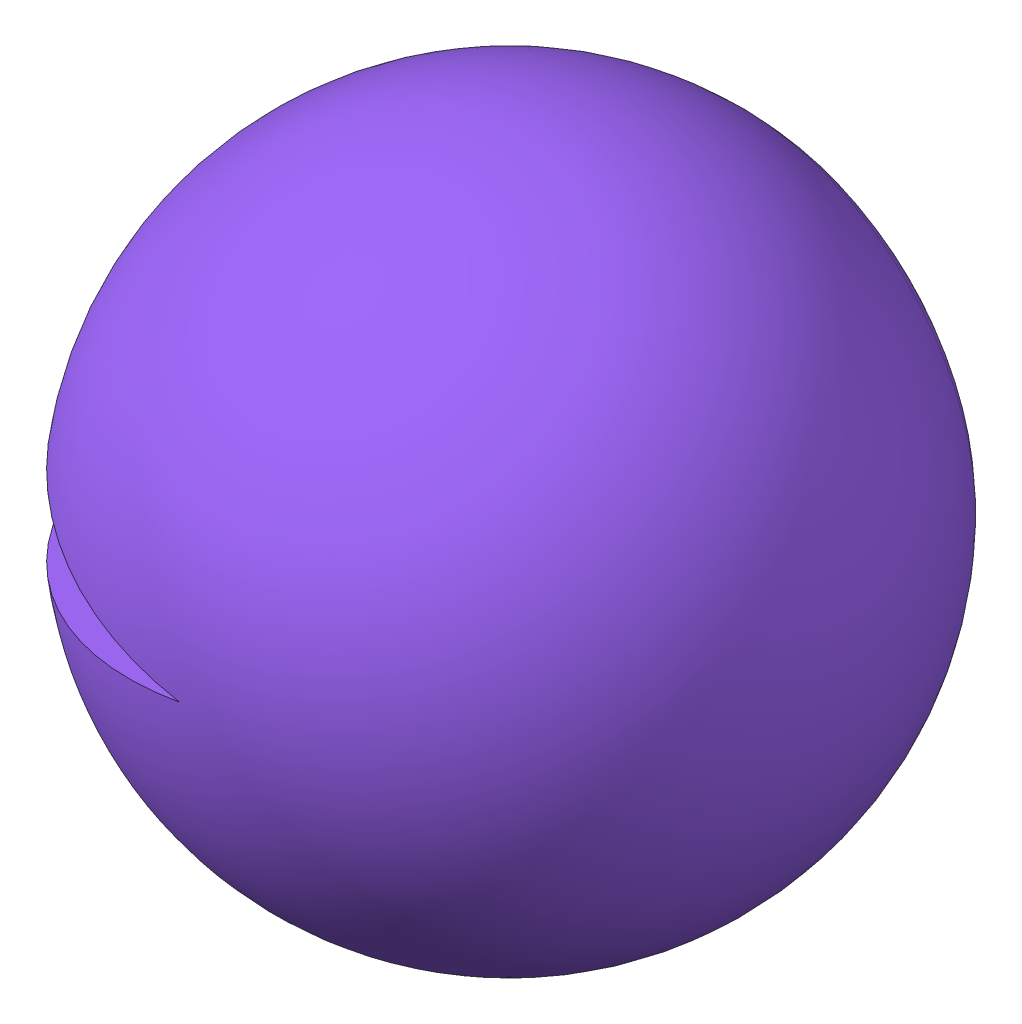
SolidWorks assembly ER3-600 机器人数模 V1.1（2016）, configuration 默认. Lengths in mm.
Overall size (1176.61 1185.62 1099.22).
8 component instances, 8 part files, 22 mates.
Components (placement in the parent):
- 底座^ER3-600 机器人数模 V1.1（2016）-1: 底座^ER3-600 机器人数模 V1.1（2016） [默认] at (-25 0 9) x (-1 0 0) z (0 1 0) size (359.06 217.5 223.77) (virtual)
- 转座^ER3-600 机器人数模 V1.1（2016）-1: 转座^ER3-600 机器人数模 V1.1（2016） [默认] at (-18 0 187.5) x (-1 0 0) z (0 1 0) size (187.42 246.08 222.85) (virtual)
- 大臂^ER3-600 机器人数模 V1.1（2016）-1: 大臂^ER3-600 机器人数模 V1.1（2016） [默认] at (-25 0 9) x (-1 0 0) z (0 1 0) size (166.87 440.16 206.04) (virtual)
- 电机座^ER3-600 机器人数模 V1.1（2016）-1: 电机座^ER3-600 机器人数模 V1.1（2016） [默认] at (0.5 57 678.5) x (1 0 0) z (0 -1 0) size (181.5 136 130.5) (virtual)
- 手腕体^ER3-600 机器人数模 V1.1（2016）-1: 手腕体^ER3-600 机器人数模 V1.1（2016） [默认] at (92.5 0 699.5) x (1 0 0) z (0 -1 0) size (246.5 104.96 129) (virtual)
- 手腕^ER3-600 机器人数模 V1.1（2016）-1: 手腕^ER3-600 机器人数模 V1.1（2016） [默认] at (295.5 0 699.5) size (112 65.5 76) (virtual)
- 法兰^ER3-600 机器人数模 V1.1（2016）-2: 法兰^ER3-600 机器人数模 V1.1（2016） [默认] at (295.5 0 699.5) size (9.5 40 40) (virtual)
- 运动范围^ER3-600 机器人数模 V1.1（2016）-1: 运动范围^ER3-600 机器人数模 V1.1（2016） [默认] x (1 0 0) z (0 -1 0) size (1176.61 1099.22 1185.62) (virtual)
Mates (geometry in assembly coordinates):
- 重合5: coordinate: point of ?
- 同心1: concentric aligned: cylinder of 底座^ER3-600 机器人数模 V1.1（2016）-1 through (0 0 121.5033) axis (0 0 -1) radius 35.25; cylinder of 转座^ER3-600 机器人数模 V1.1（2016）-1 through (0 0 369.3919) axis (0 0 -1) radius 56
- 距离1: distance = 11.5 mm anti-aligned: plane of 转座^ER3-600 机器人数模 V1.1（2016）-1 through (-18 0 192.5) normal (0 0 -1); plane of 底座^ER3-600 机器人数模 V1.1（2016）-1 through (-25 0 181) normal (0 0 1)
- LimitAngle1: limit planar angle = 0 rad aligned: plane of 底座^ER3-600 机器人数模 V1.1（2016）-1 through (-25 0 9) normal (0 1 0); plane of 转座^ER3-600 机器人数模 V1.1（2016）-1 through (-18 0 187.5) normal (0 1 0)
- 同心2: concentric aligned: cylinder of 转座^ER3-600 机器人数模 V1.1（2016）-1 through (0 -42.5 367.5) axis (0 -1 0) radius 46; cylinder of 大臂^ER3-600 机器人数模 V1.1（2016）-1 through (0 48.5 367.5) axis (0 -1 0) radius 51
- 距离2: distance = 2 mm anti-aligned: plane of 大臂^ER3-600 机器人数模 V1.1（2016）-1 through (-56.166 -42.5 311.334) normal (0 -1 0); plane of 转座^ER3-600 机器人数模 V1.1（2016）-1 through (192.5 -44.5 307.5) normal (0 1 0)
- LimitAngle2: limit planar angle = 0 rad aligned: plane of 转座^ER3-600 机器人数模 V1.1（2016）-1; plane of 大臂^ER3-600 机器人数模 V1.1（2016）-1
- 同心3: concentric aligned: cylinder of 大臂^ER3-600 机器人数模 V1.1（2016）-1 through (0 -56 662.5) axis (0 -1 0) radius 45.25; cylinder of 电机座^ER3-600 机器人数模 V1.1（2016）-1 through (0 104.1076 662.5) axis (0 -1 0) radius 46
- 距离3: distance = 2 mm anti-aligned: plane of 电机座^ER3-600 机器人数模 V1.1（2016）-1 through (0 56.5 662.5) normal (0 1 0); plane of 大臂^ER3-600 机器人数模 V1.1（2016）-1 through (50.6 58.5 611.9) normal (0 -1 0)
- LimitAngle3: limit planar angle = 0 rad aligned: plane of 大臂^ER3-600 机器人数模 V1.1（2016）-1; plane of 电机座^ER3-600 机器人数模 V1.1（2016）-1 through (0.5 57 678.5) normal (0 0 1)
- 同心4: concentric aligned: cylinder of 电机座^ER3-600 机器人数模 V1.1（2016）-1 through (-65.7939 0 699.5) axis (1 0 0) radius 42; cylinder of 手腕体^ER3-600 机器人数模 V1.1（2016）-1 through (84.5 0 699.5) axis (1 0 0) radius 41
- 距离4: distance = 1 mm anti-aligned: plane of 手腕体^ER3-600 机器人数模 V1.1（2016）-1 through (85.5 0 699.5) normal (-1 0 0); plane of 电机座^ER3-600 机器人数模 V1.1（2016）-1 through (84.5 -30 717.5) normal (1 0 0)
- LimitAngle5: limit planar angle = 0 rad aligned: plane of 手腕体^ER3-600 机器人数模 V1.1（2016）-1 through (92.5 0 699.5) normal (0 0 1); plane of 电机座^ER3-600 机器人数模 V1.1（2016）-1 through (0.5 57 678.5) normal (0 0 1)
- 同心5: concentric aligned: cylinder of 手腕体^ER3-600 机器人数模 V1.1（2016）-1 through (295.5 -32.5 699.5) axis (0 1 0) radius 24.5; cylinder of 手腕^ER3-600 机器人数模 V1.1（2016）-1 through (295.5 -32.5 699.5) axis (0 1 0) radius 24.5
- 距离5: distance = 5.5 mm anti-aligned: plane of 手腕^ER3-600 机器人数模 V1.1（2016）-1 through (295.5 27.5 699.5) normal (0 1 0); plane of 手腕体^ER3-600 机器人数模 V1.1（2016）-1 through (92.5 33 699.5) normal (0 -1 0)
- LimitAngle6: limit planar angle = 0 rad aligned: plane of 手腕^ER3-600 机器人数模 V1.1（2016）-1 through (295.5 0 699.5) normal (1 0 0); plane of 手腕体^ER3-600 机器人数模 V1.1（2016）-1
- 同心6: concentric aligned: cylinder of 手腕^ER3-600 机器人数模 V1.1（2016）-1 through (374 0 699.5) axis (-1 0 0) radius 20; cylinder of 法兰^ER3-600 机器人数模 V1.1（2016）-2 through (374 0 699.5) axis (-1 0 0) radius 20
- 距离6: distance = 4.5 mm aligned: plane of 法兰^ER3-600 机器人数模 V1.1（2016）-2 through (374 0 699.5) normal (1 0 0); plane of 手腕^ER3-600 机器人数模 V1.1（2016）-1 through (369.5 0 699.5) normal (1 0 0)
- LimitAngle9: limit planar angle = 0 rad aligned: plane of 法兰^ER3-600 机器人数模 V1.1（2016）-2 through (295.5 0 699.5) normal (0 1 0); plane of 手腕^ER3-600 机器人数模 V1.1（2016）-1 through (295.5 0 699.5) normal (0 1 0)
- 重合9: coincident: point of 底座^ER3-600 机器人数模 V1.1（2016）-1; point of 运动范围^ER3-600 机器人数模 V1.1（2016）-1
- 重合10: coincident anti-aligned: plane of 运动范围^ER3-600 机器人数模 V1.1（2016）-1 through (0 0 0) normal (0 -1 0); plane of 底座^ER3-600 机器人数模 V1.1（2016）-1 through (-25 0 9) normal (0 1 0)
- 重合11: coincident anti-aligned: plane of 底座^ER3-600 机器人数模 V1.1（2016）-1 through (-135 -70 0) normal (0 0 -1); plane of 运动范围^ER3-600 机器人数模 V1.1（2016）-1 through (0 0 0) normal (0 0 1)
